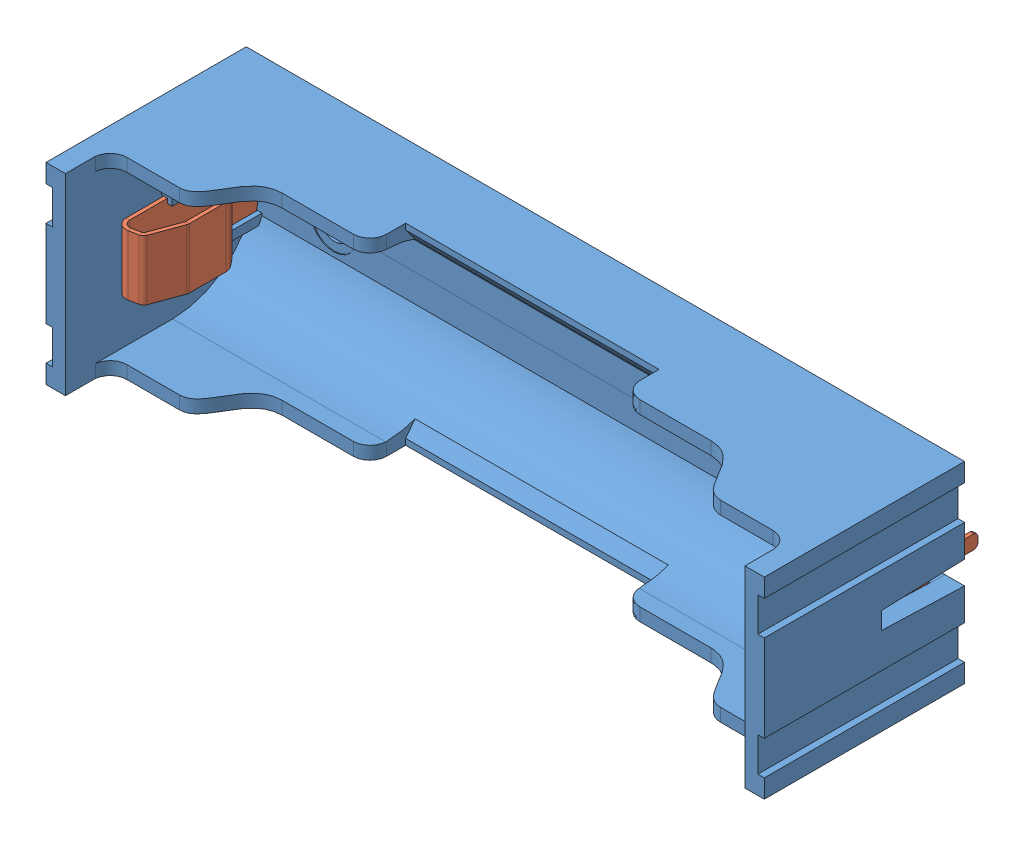
SolidWorks assembly User Library-18650 Full, configuration Holder X1. Lengths in mm.
Overall size (77.65 20.8 25.48).
3 component instances, 2 part files, 7 mates.
Components (placement in the parent):
- User Library-18650 Full_18650m-1: User Library-18650 Full_18650m [1] at (27.81 0 0) x (1 0 0) z (0 -1 0) size (77.65 21.65 20.8)
- User Library-18650 Full_18650s-1: User Library-18650 Full_18650s [По умолчанию] at (-8.24 0 4.8249) x (0 1 0) z (1 0 0) size (6.5 20.3 3.96)
- User Library-18650 Full_18650s-2: User Library-18650 Full_18650s [По умолчанию] at (63.86 0 4.8249) x (0 -1 0) z (-1 0 0) size (6.5 20.3 3.96)
Mates (geometry in assembly coordinates):
- Совпадение3: coincident: plane of User Library-18650 Full_18650m-1 through (-8.915 10.4 0) normal (0 0 -1); point of assembly
- Совпадение4: coincident: plane of 18650m-1 through (-8.24 -2.75 11.28) normal (-1 0 0); plane of 18650s-1 through (-8.24 0 4.8249) normal (1 0 0)
- Совпадение5: coincident: plane of 18650m-1 through (-8.24 -3.25 11.28) normal (0 1 0); plane of 18650s-1 through (-8.64 -3.25 8.0749) normal (0 -1 0)
- Совпадение6: coincident anti-aligned: plane of 18650m-1 through (64.535 0 1.5749) normal (0 0 1); plane of 18650s-1 through (-8.64 -3.25 1.5749) normal (0 0 -1)
- Совпадение7: coincident: plane of 18650m-1 through (63.86 3.25 11.28) normal (1 0 0); plane of 18650s-2 through (63.86 0 4.8249) normal (-1 0 0)
- Совпадение8: coincident: plane of 18650m-1 through (63.86 -3.25 11.28) normal (0 1 0); plane of 18650s-2 through (64.26 -3.25 8.0749) normal (0 -1 0)
- Совпадение9: coincident anti-aligned: plane of 18650m-1 through (64.535 0 1.5749) normal (0 0 1); plane of 18650s-2 through (64.26 3.25 1.5749) normal (0 0 -1)
